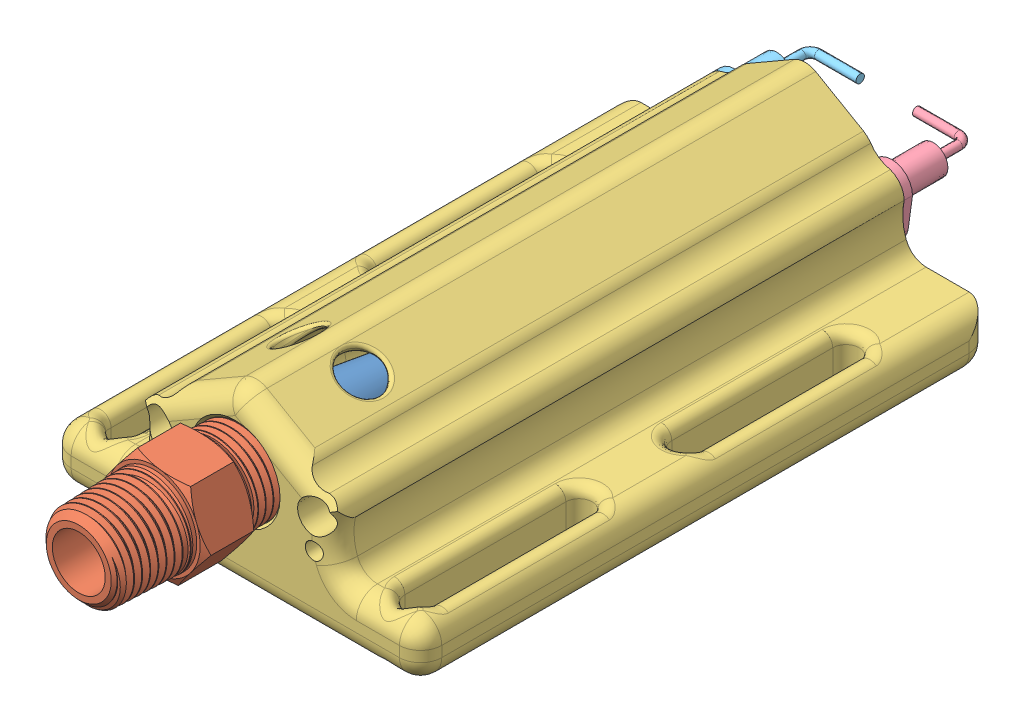
SolidWorks assembly fire head, configuration Default. Lengths in mm.
Overall size (44.45 20.38 97.72).
5 component instances, 5 part files, 12 mates.
Components (placement in the parent):
- Tweco-1: Tweco [Default] at (0 11.9738 2.2299) x (0.945772 -0.324831 0) z (0 0 1) size (8.13 8.13 27.69)
- 1-8_inch_brass_nipple-1: 1-8_inch_brass_nipple [5485K21] at (0 11.9738 14.2949) x (0 0 1) z (-0.924738 -0.380605 0) size (24.34 12.83 11.11)
- nozzleBase-1: nozzleBase [50785K141] at (0 11.9738 5.1839) size (44.45 20.38 68.66)
- sparker-1: sparker [Default] at (9.3841 11.9738 -66.7291) x (0 -1 0) z (0 0 1) size (8 8.5 44.5)
- sparker2-1: sparker2 [Default] at (-9.3841 11.9738 -66.7291) x (0 -1 0) z (0 0 1) size (8 8.5 44.5)
Mates (geometry in assembly coordinates):
- Concentric2: concentric anti-aligned: cylinder of Tweco-1 through (0 11.9738 1.8475) axis (0 0 1) radius 2.667; cylinder of 1-8_inch_brass_nipple-1 through (0 11.9738 1.8475) axis (0 0 -1) radius 3.175
- Coincident2: coincident anti-aligned: plane of Tweco-1 through (3.8436 10.6537 1.8475) normal (0 0 1); plane of 1-8_inch_brass_nipple-1 through (0 11.9738 1.8475) normal (0 0 -1)
- Coincident4: coincident: line of nozzleBase-1 through (0 11.9738 -60.7291) axis (0 0 1); plane of assembly
- Parallel1: parallel anti-aligned: line of nozzleBase-1 through (0 11.9738 -60.7291) axis (0 0 1); cylinder of sparker-1 through (9.3841 11.9738 -66.7291) axis (0 0 -1) radius 0.5
- Coincident8: coincident anti-aligned: plane of nozzleBase-1 through (0 11.9738 -60.7291) normal (0 0 -1); plane of sparker-1 through (9.3841 11.9738 -60.7291) normal (0 0 1)
- Coincident10: coincident aligned: plane of sparker-1 through (9.3841 11.9738 -61.7291) normal (0 0 -1); plane of sparker2-1 through (-9.3841 11.9738 -61.7291) normal (0 0 -1)
- Symmetric2: symmetric aligned: plane of sparker-1 through (3.3841 11.9738 -70.7291) normal (-1 0 0); plane of sparker2-1 through (-3.3841 11.9738 -70.7291) normal (1 0 0); plane of assembly through (0 0 0) normal (1 0 0)
- Concentric6: concentric aligned: cylinder of sparker-1 through (8.3841 11.9738 -70.7291) axis (-1 0 0) radius 0.5; circle of sparker2-1
- Coincident14: coincident anti-aligned: plane of nozzleBase-1 through (-22.225 0 -60.7291) normal (0 -1 0); plane of assembly through (0 0 0) normal (0 1 0)
- Concentric7: concentric anti-aligned: cylinder of nozzleBase-1 through (9.3841 11.9738 -60.7291) axis (0 0 1) radius 1.9154; cylinder of sparker-1 through (9.3841 11.9738 -26.7291) axis (0 0 -1) radius 1.75
- Concentric8: concentric aligned: cylinder of 1-8_inch_brass_nipple-1 through (0 11.9738 1.8475) axis (0 0 -1) radius 3.175; cylinder of nozzleBase-1 through (0 11.9738 -60.7291) axis (0 0 -1) radius 7
- Distance1: distance = 1.5875 mm anti-aligned: plane of Tweco-1 through (0.4204 11.8294 -18.0901) normal (0 0 -1); plane of assembly
